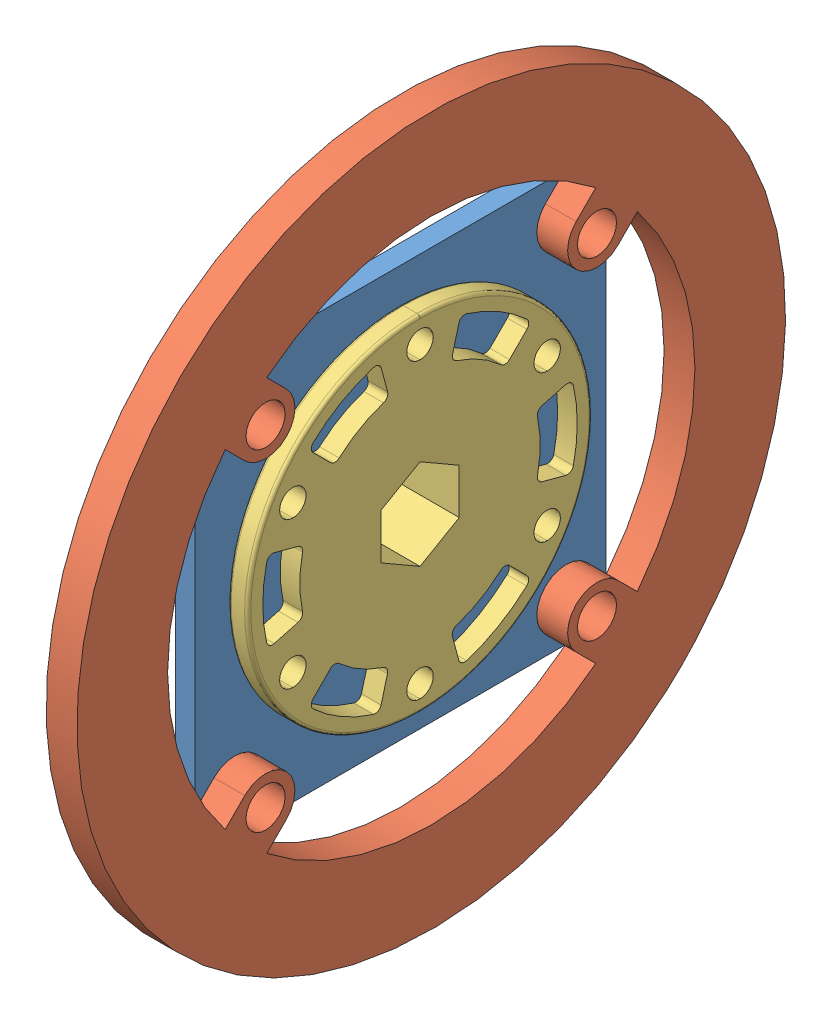
SolidWorks assembly 451-000 Large Sprocket, configuration Default. Lengths in mm.
Overall size (14.53 162.53 162.53).
3 component instances, 3 part files, 6 mates.
Components (placement in the parent):
- 451-001 Large Sprocket Adapter-1: 451-001 Large Sprocket Adapter [Default] at (17.5319 19.6047 64.5427) size (3.17 66.67 66.67)
- 451-002 Large Sprocket Model-1: 451-002 Large Sprocket Model [Default] at (23.2069 19.6047 64.5427) x (1 0 0) z (0 0.707107 0.707107) size (5 114.93 114.93)
- 900-002 1_2_Hex_Bore_Aluminum_VersaHub_217-2592-1: 900-002 1_2_Hex_Bore_Aluminum_VersaHub_217-2592 [Rev 1.1] at (11.1819 19.6047 64.5427) size (12.7 55.88 55.88)
Mates (geometry in assembly coordinates):
- Concentric1: concentric: cylinder of 451-001 Large Sprocket Adapter-1 through (20.7069 46.4747 37.6726) axis (-1 0 0) radius 3.175; cylinder of 451-002 Large Sprocket Model-1 through (25.7069 46.4747 37.6726) axis (-1 0 0) radius 3.175
- Concentric2: concentric: cylinder of 451-001 Large Sprocket Adapter-1 through (20.7069 -7.2654 91.4127) axis (-1 0 0) radius 3.175; circle of 451-002 Large Sprocket Model-1
- Coincident1: coincident: plane of 451-001 Large Sprocket Adapter-1 through (20.7069 19.6047 64.5427) normal (1 0 0); plane of 451-002 Large Sprocket Model-1 through (20.7069 19.6047 64.5427) normal (-1 0 0)
- Concentric3: concentric: cylinder of 451-001 Large Sprocket Adapter-1 through (20.7069 19.6047 64.5427) axis (-1 0 0) radius 14.3002; cylinder of 900-002 1_2_Hex_Bore_Aluminum_VersaHub_217-2592-1 through (23.8819 19.6047 64.5427) axis (1 0 0) radius 14.2949
- Coincident2: coincident: plane of 451-001 Large Sprocket Adapter-1 through (20.7069 19.6047 64.5427) normal (1 0 0); plane of 900-002 1_2_Hex_Bore_Aluminum_VersaHub_217-2592-1 through (20.7069 33.8979 64.7643) normal (-1 0 0)
- Concentric4: concentric: cylinder of 451-001 Large Sprocket Adapter-1 through (20.7069 31.5109 85.1649) axis (-1 0 0) radius 2.1828; cylinder of 900-002 1_2_Hex_Bore_Aluminum_VersaHub_217-2592-1 through (-61.9115 31.5109 85.1649) axis (1 0 0) radius 2.15
